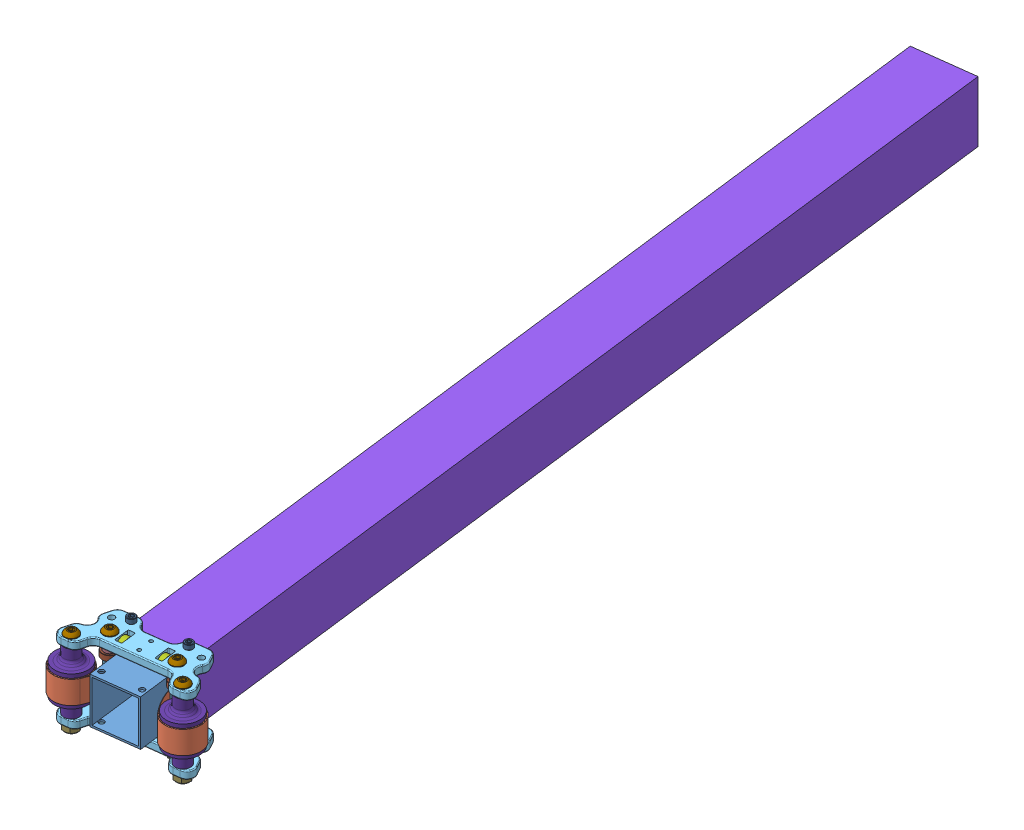
SolidWorks assembly 2 x 2 Inch Stage, configuration Default. Lengths in mm.
Overall size (183.93 74.15 806.3).
48 component instances, 20 part files, 0 mates.
Components (placement in the parent):
- 1.5_inch_stage^2 x 2 Inch Stage-1: 1.5_inch_stage^2 x 2 Inch Stage [Default] at (-107.3783 0 -858.4701) size (133.34 47.37 731.79) (virtual)
  - 1.5x1.5 bar^1.5_inch_stage_2 x 2 Inch Stage-1: 1.5x1.5 bar^1.5_inch_stage_2 x 2 Inch Stage [Default] at (575.8182 404.7167 1377.5179) x (-0.992268 0 0.124114) z (-0.124114 0 -0.992268) size (38.1 38.1 711.2) (virtual)
  - 2x2StageInternalEndBlock^1.5_inch_stage_2 x 2 Inch Stage-1: 2x2StageInternalEndBlock^1.5_inch_stage_2 x 2 Inch Stage [Default] at (413.7616 573.8056 681.0462) x (-0.992268 0 0.124114) z (-0.124114 0 -0.992268) size (47.37 47.37 40.64) (virtual)
  - 94615A115_Brass Flanged Screw-to-Expand Inserts (1)^1.5_inch_stage_2 x 2 Inch Stage-1: 94615A115_Brass Flanged Screw-to-Expand Inserts (1)^1.5_inch_stage_2 x 2 Inch Stage [Default] at (431.7042 573.8056 688.4011) x (0.114575 0.384452 0.916007) z (-0.047716 0.923145 -0.381479) size (7.92 9.53 7.92) (virtual)
  - 97763A231_18-8 Stainless Steel Button Head Hex Drive Screws^1.5_inch_stage_2 x 2 Inch Stage-1: 97763A231_18-8 Stainless Steel Button Head Hex Drive Screws^1.5_inch_stage_2 x 2 Inch Stage [Default] at (398.9269 573.8691 692.501) x (0.124114 0.000773 0.992268) z (-0.992268 0 0.124114) size (9.17 9.17 12.09) (virtual)
- 2x2ClimberPlateAssemblyNew^2 x 2 Inch Stage-1: 2x2ClimberPlateAssemblyNew^2 x 2 Inch Stage [Default] at (310.1471 56.4224 225.65) x (0.992268 0 -0.124114) z (0.124114 0 0.992268) size (102.18 13.04 44.45) (virtual)
  - 2x2NewClimberPlateConcept^2x2ClimberPlateAssemblyNew_2 x 2 Inch Stage-1: 2x2NewClimberPlateConcept^2x2ClimberPlateAssemblyNew_2 x 2 Inch Stage [Default] at (71.6924 542.7705 -285.0056) x (-1 0 0) z (0 1 0) size (102.18 44.45 8.76) (virtual)
  - 98381A545_ALLOY STEEL DOWEL PIN^2x2ClimberPlateAssemblyNew_2 x 2 Inch Stage-1: 98381A545_ALLOY STEEL DOWEL PIN^2x2ClimberPlateAssemblyNew_2 x 2 Inch Stage [Default] at (46.4194 542.6435 281.8589) x (-1 0 0) z (0 -0.467381 0.884056) size (34.92 6.35 6.35) (virtual)
  - TTB-0027_.50OD_.25ID_.188WD^2x2ClimberPlateAssemblyNew_2 x 2 Inch Stage-1: TTB-0027_.50OD_.25ID_.188WD^2x2ClimberPlateAssemblyNew_2 x 2 Inch Stage [Default] at (31.3382 542.6435 281.8589) x (0 0.013886 0.999904) z (-1 0 0) size (12.7 12.7 4.76) (virtual)
  - TTB-0027_.50OD_.25ID_.188WD^2x2ClimberPlateAssemblyNew_2 x 2 Inch Stage-2: TTB-0027_.50OD_.25ID_.188WD^2x2ClimberPlateAssemblyNew_2 x 2 Inch Stage [Default] at (61.5007 542.6435 281.8589) x (0 0.005291 0.999986) z (-1 0 0) size (12.7 12.7 4.76) (virtual)
- 2x2ClimberPlateAssemblyNew^2 x 2 Inch Stage-2: 2x2ClimberPlateAssemblyNew^2 x 2 Inch Stage [Default] at (402.0161 1091.1635 214.1589) x (-0.992268 0 0.124114) z (0.124114 0 0.992268) size (102.18 13.04 44.45) (virtual)
  - 2x2NewClimberPlateConcept^2x2ClimberPlateAssemblyNew_2 x 2 Inch Stage-1: 2x2NewClimberPlateConcept^2x2ClimberPlateAssemblyNew_2 x 2 Inch Stage [Default] at (71.6924 542.7705 -285.0056) x (-1 0 0) z (0 1 0) size (102.18 44.45 8.76) (virtual)
  - 98381A545_ALLOY STEEL DOWEL PIN^2x2ClimberPlateAssemblyNew_2 x 2 Inch Stage-1: 98381A545_ALLOY STEEL DOWEL PIN^2x2ClimberPlateAssemblyNew_2 x 2 Inch Stage [Default] at (46.4194 542.6435 281.8589) x (-1 0 0) z (0 -0.467381 0.884056) size (34.92 6.35 6.35) (virtual)
  - TTB-0027_.50OD_.25ID_.188WD^2x2ClimberPlateAssemblyNew_2 x 2 Inch Stage-1: TTB-0027_.50OD_.25ID_.188WD^2x2ClimberPlateAssemblyNew_2 x 2 Inch Stage [Default] at (31.3382 542.6435 281.8589) x (0 0.013886 0.999904) z (-1 0 0) size (12.7 12.7 4.76) (virtual)
  - TTB-0027_.50OD_.25ID_.188WD^2x2ClimberPlateAssemblyNew_2 x 2 Inch Stage-2: TTB-0027_.50OD_.25ID_.188WD^2x2ClimberPlateAssemblyNew_2 x 2 Inch Stage [Default] at (61.5007 542.6435 281.8589) x (0 0.005291 0.999986) z (-1 0 0) size (12.7 12.7 4.76) (virtual)
- 2x2 Box^2 x 2 Inch Stage-1: 2x2 Box^2 x 2 Inch Stage [Default] at (320.6921 548.3929 -267.6788) x (-0.992268 0 0.124114) z (0.124114 0 0.992268) size (50.8 50.8 762) (virtual)
- 91255A529_NO THREADS_Button Head Hex Drive Screw (1)^2 x 2 Inch Stage-1: 91255A529_NO THREADS_Button Head Hex Drive Screw (1)^2 x 2 Inch Stage [Default] at (366.1553 609.0227 504.1716) x (0.396837 0 -0.917889) z (0 1 0) size (11.1 11.1 73.2) (virtual)
- 90044A515_Black-Oxide Alloy Steel Socket Head Screw^2 x 2 Inch Stage-1: 90044A515_Black-Oxide Alloy Steel Socket Head Screw^2 x 2 Inch Stage [Default] at (410.673 605.6699 482.6046) x (0.993633 0 -0.112668) z (0 1 0) size (6.86 6.86 74.15) (virtual)
- 90044A515_Black-Oxide Alloy Steel Socket Head Screw^2 x 2 Inch Stage-2: 90044A515_Black-Oxide Alloy Steel Socket Head Screw^2 x 2 Inch Stage [Default] at (367.8773 605.6699 487.9575) x (0.430705 0 0.902493) z (0 1 0) size (6.86 6.86 74.15) (virtual)
- 91255A529_NO THREADS_Button Head Hex Drive Screw (1)^2 x 2 Inch Stage-2: 91255A529_NO THREADS_Button Head Hex Drive Screw (1)^2 x 2 Inch Stage [Default] at (351.7432 609.0227 521.973) x (-0.099638 0 0.995024) z (0 1 0) size (11.1 11.1 73.2) (virtual)
- 91255A529_NO THREADS_Button Head Hex Drive Screw (1)^2 x 2 Inch Stage-3: 91255A529_NO THREADS_Button Head Hex Drive Screw (1)^2 x 2 Inch Stage [Default] at (434.6883 609.0227 511.5981) x (1 0 0) z (0 1 0) size (11.1 11.1 73.2) (virtual)
- 91255A529_NO THREADS_Button Head Hex Drive Screw (1)^2 x 2 Inch Stage-4: 91255A529_NO THREADS_Button Head Hex Drive Screw (1)^2 x 2 Inch Stage [Default] at (416.3356 609.0227 497.895) x (0.998718 0 -0.050617) z (0 1 0) size (11.1 11.1 73.2) (virtual)
- TTB-0027_.50OD_.25ID_.188WD^2 x 2 Inch Stage-1: TTB-0027_.50OD_.25ID_.188WD^2 x 2 Inch Stage [Default] at (416.3356 557.2004 497.895) x (-0.032207 0 0.999481) z (0 1 0) size (12.7 12.7 4.76) (virtual)
- TTB-0027_.50OD_.25ID_.188WD^2 x 2 Inch Stage-2: TTB-0027_.50OD_.25ID_.188WD^2 x 2 Inch Stage [Default] at (416.3356 590.4617 497.895) x (-0.065423 0 0.997858) z (0 1 0) size (12.7 12.7 4.76) (virtual)
- TTB-0027_.50OD_.25ID_.188WD^2 x 2 Inch Stage-3: TTB-0027_.50OD_.25ID_.188WD^2 x 2 Inch Stage [Default] at (366.1553 557.2004 504.1716) x (-0.065423 0 0.997858) z (0 1 0) size (12.7 12.7 4.76) (virtual)
- TTB-0027_.50OD_.25ID_.188WD^2 x 2 Inch Stage-4: TTB-0027_.50OD_.25ID_.188WD^2 x 2 Inch Stage [Default] at (366.1553 590.4617 504.1716) x (-0.065423 0 0.997858) z (0 1 0) size (12.7 12.7 4.76) (virtual)
- 90101A230_18-8 Stainless Steel Thin Nylon-Insert Locknut^2 x 2 Inch Stage-1: 90101A230_18-8 Stainless Steel Thin Nylon-Insert Locknut^2 x 2 Inch Stage [Default] at (434.6883 541.9159 511.5981) x (0.797272 0 -0.60362) z (-0.60362 0 -0.797272) size (11.11 5.2 12.83) (virtual)
- 90101A230_18-8 Stainless Steel Thin Nylon-Insert Locknut^2 x 2 Inch Stage-2: 90101A230_18-8 Stainless Steel Thin Nylon-Insert Locknut^2 x 2 Inch Stage [Default] at (416.3356 541.9159 497.895) x (0.921386 0 0.388648) z (0.388648 0 -0.921386) size (11.11 5.2 12.83) (virtual)
- 90101A230_18-8 Stainless Steel Thin Nylon-Insert Locknut^2 x 2 Inch Stage-3: 90101A230_18-8 Stainless Steel Thin Nylon-Insert Locknut^2 x 2 Inch Stage [Default] at (351.7432 541.9159 521.973) x (0.797272 0 -0.60362) z (-0.60362 0 -0.797272) size (11.11 5.2 12.83) (virtual)
- 90101A230_18-8 Stainless Steel Thin Nylon-Insert Locknut^2 x 2 Inch Stage-4: 90101A230_18-8 Stainless Steel Thin Nylon-Insert Locknut^2 x 2 Inch Stage [Default] at (366.1553 541.9159 504.1716) x (0.797272 0 -0.60362) z (-0.60362 0 -0.797272) size (11.11 5.2 12.83) (virtual)
- QuaterInchTelescopingSpacer^2 x 2 Inch Stage-1: QuaterInchTelescopingSpacer^2 x 2 Inch Stage [Default] at (391.2422 599.1929 504.1716) x (1 0 0) z (0 -1 0) size (9.27 9.27 6.35) (virtual)
- QuaterInchTelescopingSpacer^2 x 2 Inch Stage-2: QuaterInchTelescopingSpacer^2 x 2 Inch Stage [Default] at (391.2422 554.8191 504.1844) x (1 0 0.000511) z (0 -1 0) size (9.27 9.27 6.35) (virtual)
- 1.122InchTelescopingSpacer^2 x 2 Inch Stage-1: 1.122InchTelescopingSpacer^2 x 2 Inch Stage [Default] at (391.2422 588.0804 504.1716) x (1 0 0) z (0 -1 0) size (8.76 8.76 28.5) (virtual)
- QuaterInchTelescopingSpacer^2 x 2 Inch Stage-3: QuaterInchTelescopingSpacer^2 x 2 Inch Stage [Default] at (440.4399 599.1929 504.8475) x (0.96083 0 0.277139) z (0 -1 0) size (9.27 9.27 6.35) (virtual)
- QuaterInchTelescopingSpacer^2 x 2 Inch Stage-4: QuaterInchTelescopingSpacer^2 x 2 Inch Stage [Default] at (409.5553 554.8191 522.0482) x (-0.270275 0 0.962783) z (0 -1 0) size (9.27 9.27 6.35) (virtual)
- 94615A115_Brass Flanged Screw-to-Expand Inserts (1)^2 x 2 Inch Stage-1: 94615A115_Brass Flanged Screw-to-Expand Inserts (1)^2 x 2 Inch Stage [Default] at (290.8052 573.8056 -165.8762) x (0.123955 0.050546 0.991) z (0.006274 -0.998722 0.050156) size (7.92 9.53 7.92) (virtual)
- 97763A231_18-8 Stainless Steel Button Head Hex Drive Screws^2 x 2 Inch Stage-1: 97763A231_18-8 Stainless Steel Button Head Hex Drive Screws^2 x 2 Inch Stage [Default] at (323.7085 573.8691 -169.9917) x (-0.124114 0 -0.992268) z (0.992268 0 -0.124114) size (9.17 9.17 12.09) (virtual)
- 1.122InchTelescopingSpacer^2 x 2 Inch Stage-2: 1.122InchTelescopingSpacer^2 x 2 Inch Stage [Default] at (441.4226 588.0804 497.895) x (1 0 0) z (0 -1 0) size (8.76 8.76 28.5) (virtual)
- 1InchCFSpringRetentionSpacer_BaseStage^2 x 2 Inch Stage-1: 1InchCFSpringRetentionSpacer_BaseStage^2 x 2 Inch Stage [Default] at (351.7432 564.2679 521.973) x (1 0 0) z (0 -1 0) size (27.94 27.94 15.88) (virtual)
- 1InchCFSpringRetentionSpacer_BaseStage^2 x 2 Inch Stage-2: 1InchCFSpringRetentionSpacer_BaseStage^2 x 2 Inch Stage [Default] at (434.6883 583.3179 511.5981) x (-0.043542 0 0.999052) z (0 1 0) size (27.94 27.94 15.88) (virtual)
- 1InchCFSpringRetentionSpacer_BaseStage^2 x 2 Inch Stage-3: 1InchCFSpringRetentionSpacer_BaseStage^2 x 2 Inch Stage [Default] at (351.7432 583.3179 521.973) x (1 0 0) z (0 1 0) size (27.94 27.94 15.88) (virtual)
- 1InchCFSpringRetentionSpacer_BaseStage^2 x 2 Inch Stage-4: 1InchCFSpringRetentionSpacer_BaseStage^2 x 2 Inch Stage [Default] at (434.6883 564.2679 511.5981) x (0.999991 0 -0.00417) z (0 -1 0) size (27.94 27.94 15.88) (virtual)
- 90101A009_18-8 Stainless Steel Thin Nylon-Insert Locknut (1)^2 x 2 Inch Stage-1: 90101A009_18-8 Stainless Steel Thin Nylon-Insert Locknut (1)^2 x 2 Inch Stage [Default] at (368.252 541.9159 487.9106) x (0.797272 0 -0.60362) z (-0.60362 0 -0.797272) size (8.73 4.37 10.08) (virtual)
- 9293K56_SpringRoller^2 x 2 Inch Stage-1: 9293K56_SpringRoller^2 x 2 Inch Stage [Default] at (351.7432 564.2679 521.973) x (0.41705 0 -0.908884) z (0 1 0) size (20.07 20.07 19.05) (virtual)
- 9293K56_SpringRoller^2 x 2 Inch Stage-2: 9293K56_SpringRoller^2 x 2 Inch Stage [Default] at (434.6883 583.3179 511.5981) x (0.41705 0 0.908884) z (0 -1 0) size (20.07 20.07 19.05) (virtual)
- 9293K56_Constant-Force Spring^2 x 2 Inch Stage-1: 9293K56_Constant-Force Spring^2 x 2 Inch Stage [Default] at (434.7326 573.7929 511.5599) x (0 -1 0) z (-0.934501 0 0.355959) size (19.06 41.04 33.21) (virtual)
- 9293K56_Constant-Force Spring^2 x 2 Inch Stage-2: 9293K56_Constant-Force Spring^2 x 2 Inch Stage [Default] at (351.6902 573.7929 521.9484) x (0 1 0) z (0.996341 0 0.085466) size (19.06 41.04 33.21) (virtual)
- 90101A009_18-8 Stainless Steel Thin Nylon-Insert Locknut (1)^2 x 2 Inch Stage-2: 90101A009_18-8 Stainless Steel Thin Nylon-Insert Locknut (1)^2 x 2 Inch Stage [Default] at (410.673 541.9159 482.6046) x (0.797272 0 -0.60362) z (-0.60362 0 -0.797272) size (8.73 4.37 10.08) (virtual)
